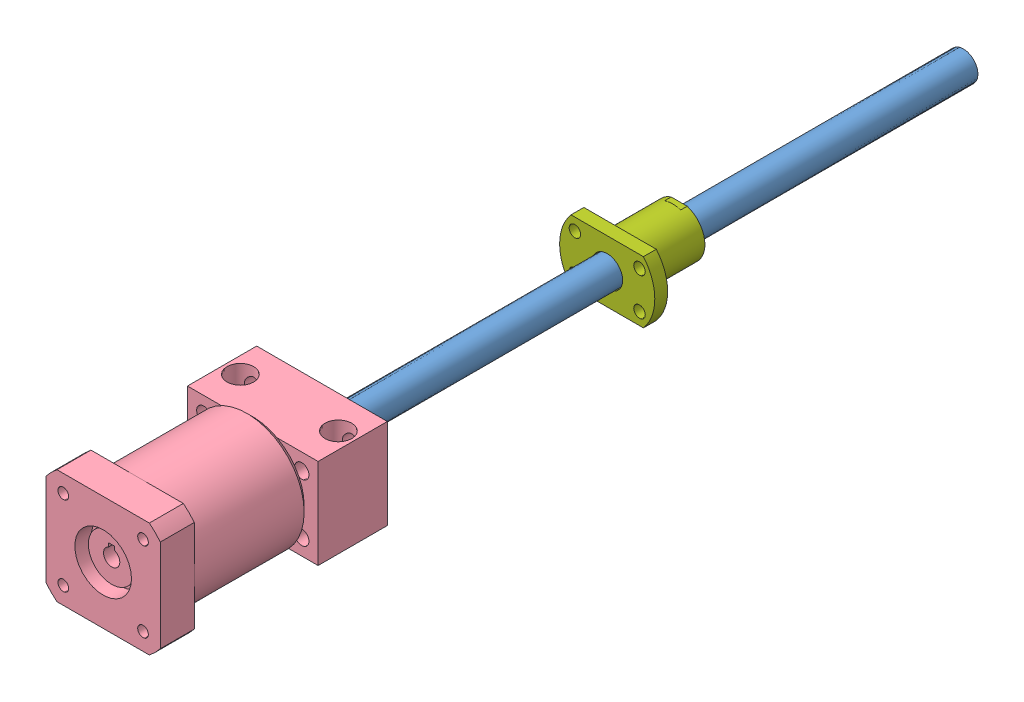
SolidWorks assembly PMBS12x5R_3FW_0_T10_U1_00_300_0_S_b3, configuration Valor predeterminado. Lengths in mm.
Overall size (50.8 44.45 334.47).
8 component instances, 7 part files, 3 mates.
Components (placement in the parent):
- Screw_PMBS 12x5R_b3-1: Screw_PMBS 12x5R_b3 [Valor predeterminado] at (0 0 -368.25) size (11.33 11.33 249)
- EndCode1_8-U1_b3-1: EndCode1_8-U1_b3 [Valor predeterminado] at (0 0 -119.25) x (0 0 1) z (-1 0 0) size (85.47 44.45 50.8)
  - Place Holder_b3-1: Place Holder_b3 [Valor predeterminado] at origin size (0.38 0.51 0.51)
  - EndMachining_8-3K_b3-1: EndMachining_8-3K_b3 [Valor predeterminado] x (0 0 1) z (-1 0 0) size (8 8 50.8)
  - EZM_EZM-1008-17_b3-1: EZM_EZM-1008-17_b3 [Valor predeterminado] at (27.305 -17.4498 25.4) x (0 0 -1) z (1 0 0) size (50.8 44.45 85.09)
  - LockNut(1)_N-00.8_b3-1: LockNut(1)_N-00.8_b3 [Valor predeterminado] at (28.8798 0 0) x (1 0 0) z (0 0.998865 0.047634) size (7.05 16.48 14.68)
  - Spacer_b3-1: Spacer_b3 [Valor predeterminado] at origin size (28.88 9.91 9.91)
- Nut_MBN12x5R-3FW_b3-1: Nut_MBN12x5R-3FW_b3 [Valor predeterminado] at (0 0 -229.75) x (0 0 -1) z (1 0 0) size (28 24 37)
Mates (geometry in assembly coordinates):
- Concêntrico1: concentric aligned: cylinder of Screw_PMBS 12x5R_b3-1 through (0 0 -119.25) axis (0 0 -1) radius 5.665; cylinder of EndCode1_8-U1_b3-1/EndMachining_8-3K_b3-1 through (0 0 -119.25) axis (0 0 -1) radius 3.175
- Coincidente1: coincident anti-aligned: plane of Screw_PMBS 12x5R_b3-1 through (0 0 -119.25) normal (0 0 1); plane of EndCode1_8-U1_b3-1/EndMachining_8-3K_b3-1 through (0 0 -119.25) normal (0 0 -1)
- Concêntrico2: concentric anti-aligned: cylinder of Screw_PMBS 12x5R_b3-1 through (0 0 -119.25) axis (0 0 -1) radius 5.665; cylinder of Nut_MBN12x5R-3FW_b3-1 through (0 0 -257.75) axis (0 0 1) radius 6
